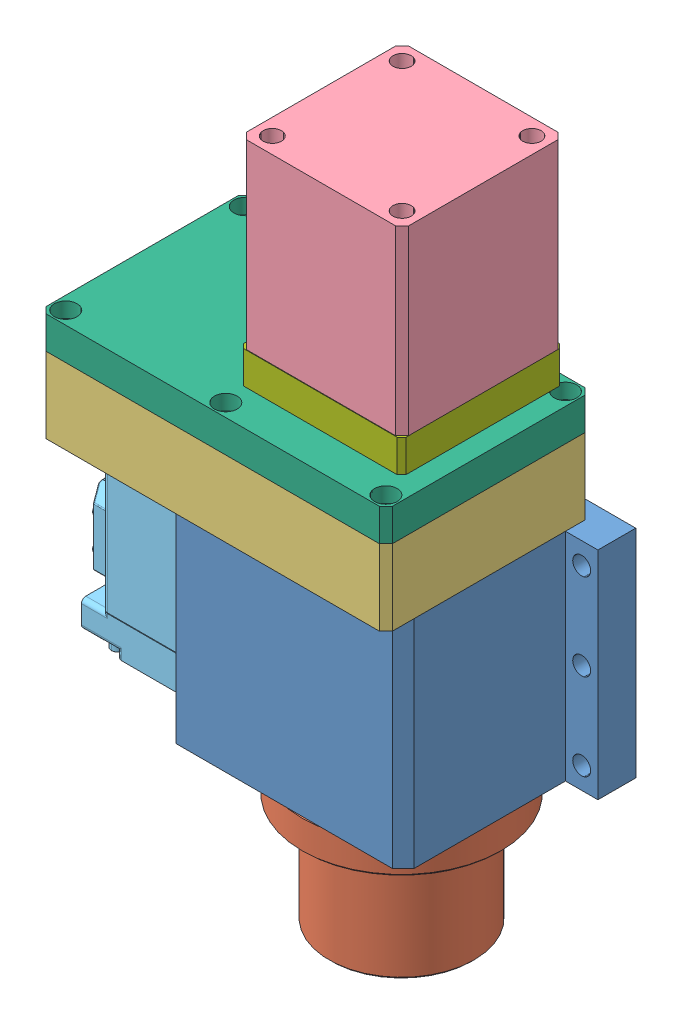
SolidWorks assembly DNM-65, configuration Default. Lengths in mm.
Overall size (189.85 314 100.5).
9 component instances, 9 part files, 23 mates.
Components (placement in the parent):
- DNM-65-1: DNM-65 [默认] at (14.1024 154.633 73.7637) size (140 100 92.5)
- DNM-65-M-1: DNM-65-M [默认] at (92.1024 -10.367 120.0137) x (1 0 0) z (0 1 0) size (92 92 220)
- DNM-65-C-1: DNM-65-C [默认] at (-20.8976 189.633 139.2637) x (1 0 0) z (0 -1 0) size (160 95 35)
- AT-1: AT [默认] at (54.6024 303.633 82.2637) x (0 0 1) z (0 -1 0) size (75 75 84)
- ser400w.step-1: ser400w.step [默认] at (-35.7442 129.1813 -8.3338) x (0 1 0) z (0 0 1) size (118.6 79.85 60.01)
- AD-1: AD [默认] at (-20.8976 204.633 174.2637) x (1 0 0) z (0 -1 0) size (160 95 15)
- SDATT-1: SDATT [默认] at (54.6024 219.633 157.5137) x (1 0 0) z (0 -1 0) size (75 75 15)
- 电机侧多锲带轮-1: 电机侧多锲带轮 [默认] at (14.1024 183.633 129.9887) x (1 0 0) z (0 -1 0) size (50 50 25)
- 主轴多锲带轮-1: 主轴多锲带轮 [默认] at (92.1024 183.633 120.0137) x (1 0 0) z (0 -1 0) size (41 41 28)
Mates (geometry in assembly coordinates):
- 同心1: concentric anti-aligned: cylinder of DNM-65-1 through (92.1024 54.633 120.0137) axis (0 1 0) radius 32.525; cylinder of DNM-65-M-1 through (92.1024 138.633 120.0137) axis (0 -1 0) radius 32.5
- 重合1: coincident anti-aligned: plane of DNM-65-1 through (14.1024 54.633 166.2637) normal (0 -1 0); plane of DNM-65-M-1 through (92.1024 54.633 120.0137) normal (0 1 0)
- 同心2: concentric aligned: circle of DNM-65-1; circle of DNM-65-M-1
- 平行1: parallel aligned: plane of DNM-65-C-1 through (-20.8976 154.633 139.2637) normal (-1 0 0); plane of ser400w.step-1 through (-15.8976 -1.8198 159.9887) normal (-1 0 0)
- 距离4: distance = 8 mm aligned: plane of DNM-65-1 through (14.1024 154.633 166.2637) normal (0 0 1); plane of DNM-65-C-1 through (47.1024 154.633 174.2637) normal (0 0 1)
- 重合19: coincident aligned: plane of DNM-65-1 through (139.1024 154.633 91.2637) normal (1 0 0); plane of DNM-65-C-1 through (139.1024 154.633 79.2637) normal (1 0 0)
- 距离5: distance = 0.025 mm anti-aligned: plane of DNM-65-1 through (44.1024 154.633 99.9637) normal (0 0 1); plane of ser400w.step-1 through (-15.8976 -1.8198 99.9887) normal (0 0 -1)
- 重合21: coincident anti-aligned: plane of DNM-65-1 through (44.1024 154.633 73.7637) normal (-1 0 0); plane of ser400w.step-1 through (44.1024 -1.8198 159.9887) normal (1 0 0)
- 距离7: distance = 9.5 mm aligned: plane of AT-1 through (129.6024 219.633 82.2637) normal (1 0 0); plane of DNM-65-C-1 through (139.1024 154.633 79.2637) normal (1 0 0)
- 重合26: coincident anti-aligned: plane of DNM-65-C-1 through (-20.8976 189.633 139.2637) normal (0 1 0); plane of AD-1 through (-20.8976 189.633 174.2637) normal (0 -1 0)
- 重合27: coincident aligned: plane of DNM-65-C-1 through (139.1024 154.633 79.2637) normal (1 0 0); plane of AD-1 through (139.1024 189.633 174.2637) normal (1 0 0)
- 重合28: coincident aligned: plane of DNM-65-C-1 through (139.1024 154.633 79.2637) normal (0 0 -1); plane of AD-1 through (-20.8976 189.633 79.2637) normal (0 0 -1)
- 距离8: distance = 3 mm aligned: plane of AD-1 through (-20.8976 189.633 79.2637) normal (0 0 -1); plane of AT-1 through (54.6024 219.633 82.2637) normal (0 0 -1)
- 重合30: coincident anti-aligned: plane of DNM-65-1 through (14.1024 154.633 166.2637) normal (0 1 0); plane of DNM-65-C-1 through (-20.8976 154.633 139.2637) normal (0 -1 0)
- 重合31: coincident anti-aligned: plane of AD-1 through (-20.8976 204.633 174.2637) normal (0 1 0); plane of SDATT-1 through (54.6024 204.633 157.5137) normal (0 -1 0)
- 同心3: concentric anti-aligned: cylinder of AD-1 through (92.1024 189.633 120.0137) axis (0 1 0) radius 12.5; cylinder of SDATT-1 through (92.1024 219.633 120.0137) axis (0 -1 0) radius 12.5
- 平行2: parallel aligned: plane of AD-1 through (139.1024 189.633 174.2637) normal (1 0 0); plane of SDATT-1 through (129.6024 204.633 157.5137) normal (1 0 0)
- 重合33: coincident anti-aligned: plane of AT-1 through (54.6024 219.633 82.2637) normal (0 -1 0); plane of SDATT-1 through (54.6024 219.633 157.5137) normal (0 1 0)
- 同心4: concentric anti-aligned: cylinder of ser400w.step-1 through (14.1024 214.6024 129.9887) axis (0 1 0) radius 7; circle of 电机侧多锲带轮-1
- 重合35: coincident anti-aligned: plane of DNM-65-C-1 through (-20.8976 154.633 139.2637) normal (0 -1 0); plane of ser400w.step-1 through (-10.8976 154.633 129.9887) normal (0 1 0)
- 同心5: concentric anti-aligned: cylinder of DNM-65-M-1 through (92.1024 209.633 120.0137) axis (0 -1 0) radius 9; cylinder of 主轴多锲带轮-1 through (92.1024 155.633 120.0137) axis (0 1 0) radius 11.525
- 重合36: coincident anti-aligned: plane of DNM-65-M-1 through (92.1024 155.633 120.0137) normal (0 1 0); circle of 主轴多锲带轮-1
- 重合37: coincident aligned: plane of 电机侧多锲带轮-1 through (14.1024 183.633 129.9887) normal (0 1 0); plane of 主轴多锲带轮-1 through (92.1024 183.633 120.0137) normal (0 1 0)
